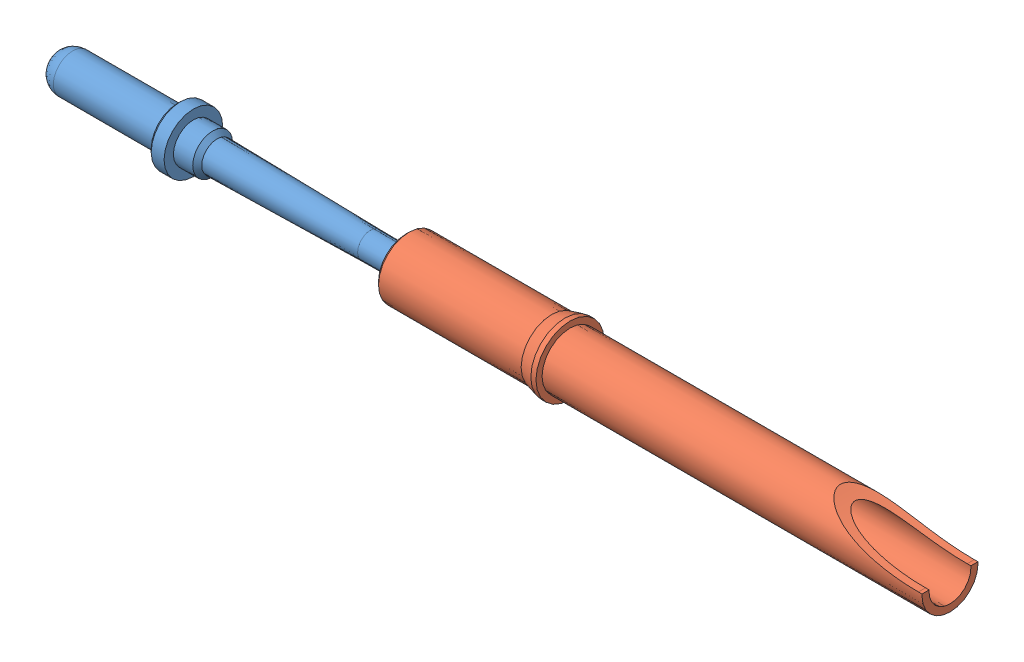
SolidWorks assembly 90049 Clip-in-line, configuration Default. Lengths in mm.
Overall size (13.98 1.06 1.06).
2 component instances, 2 part files, 0 mates.
Components (placement in the parent):
- 50254-1: 50254 [Default] at origin size (7.79 0.91 0.91)
- 65007-1: 65007 [Default] at (5.45 0 0) size (8.53 1.06 1.06)
